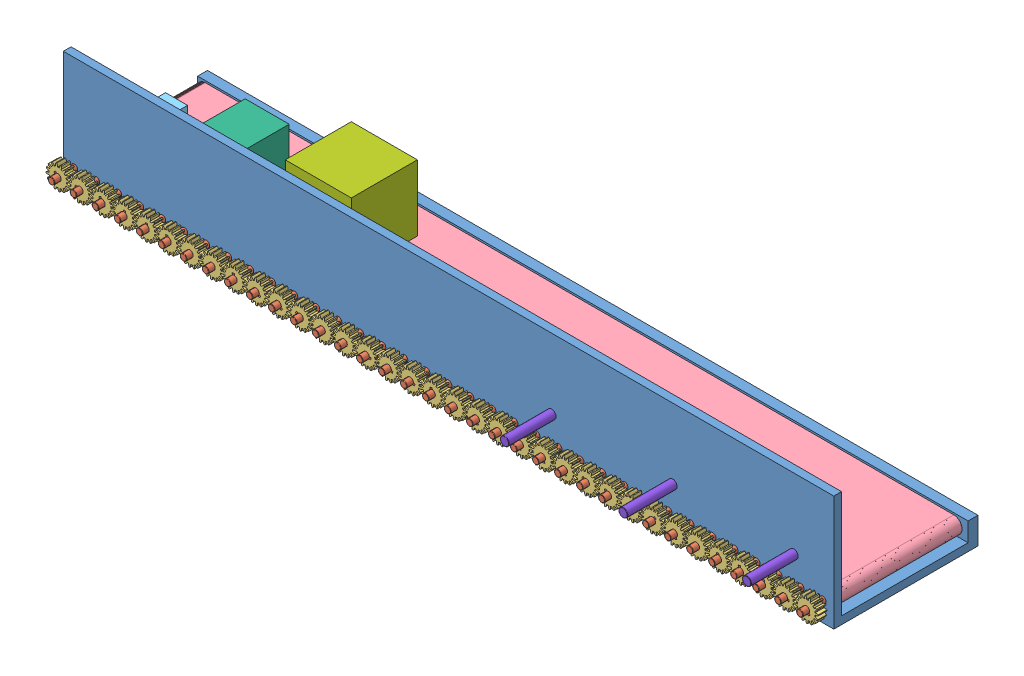
SolidWorks assembly Sorting Assembly, configuration Default. Lengths in mm.
Overall size (3549.93 523.7 880.63).
113 component instances, 8 part files, 186 mates.
Components (placement in the parent):
- part7-1: part7 [Default] at (1006.6553 1787.6179 2565.5497) size (3500 523.7 655)
- roller-37: roller [Default] at (-193.3447 1492.6179 3165.5497) x (-0.262739 0.964867 0) z (0 0 -1) size (75 75 750)
- roller-38: roller [Default] at (-593.3447 1492.6179 3165.5497) x (-0.948434 0.316975 0) z (0 0 -1) size (75 75 750)
- roller-39: roller [Default] at (-393.3447 1492.6179 3165.5497) x (0.151532 0.988452 0) z (0 0 -1) size (75 75 750)
- roller-40: roller [Default] at (-493.3447 1492.6179 3165.5497) x (-0.412809 0.910818 0) z (0 0 -1) size (75 75 750)
- roller-41: roller [Default] at (-293.3447 1492.6179 3165.5497) x (0.164944 0.986303 0) z (0 0 -1) size (75 75 750)
- roller-42: roller [Default] at (206.6553 1492.6179 3165.5497) x (0.853814 -0.520577 0) z (0 0 -1) size (75 75 750)
- roller-43: roller [Default] at (-93.3447 1492.6179 3165.5497) x (-0.222258 -0.974988 0) z (0 0 -1) size (75 75 750)
- roller-44: roller [Default] at (6.6553 1492.6179 3165.5497) x (-0.857308 -0.514803 0) z (0 0 -1) size (75 75 750)
- roller-45: roller [Default] at (106.6553 1492.6179 3165.5497) x (-0.150084 0.988673 0) z (0 0 -1) size (75 75 750)
- roller-46: roller [Default] at (406.6553 1492.6179 3165.5497) x (-0.853759 0.520669 0) z (0 0 -1) size (75 75 750)
- roller-47: roller [Default] at (306.6553 1492.6179 3165.5497) x (0.816925 -0.576744 0) z (0 0 -1) size (75 75 750)
- roller-48: roller [Default] at (706.6553 1492.6179 3165.5497) x (0.984729 -0.174094 0) z (0 0 -1) size (75 75 750)
- roller-49: roller [Default] at (806.6553 1492.6179 3165.5497) x (0.935909 -0.352242 0) z (0 0 -1) size (75 75 750)
- roller-50: roller [Default] at (506.6553 1492.6179 3165.5497) x (-0.352824 -0.93569 0) z (0 0 -1) size (75 75 750)
- roller-51: roller [Default] at (606.6553 1492.6179 3165.5497) x (-0.991808 -0.127741 0) z (0 0 -1) size (75 75 750)
- roller-52: roller [Default] at (1006.6553 1492.6179 3165.5497) x (-0.232726 0.972542 0) z (0 0 -1) size (75 75 750)
- roller-53: roller [Default] at (1106.6553 1492.6179 3165.5497) x (-0.541816 -0.840497 0) z (0 0 -1) size (75 75 750)
- roller-54: roller [Default] at (906.6553 1492.6179 3165.5497) x (0.950307 -0.311315 0) z (0 0 -1) size (75 75 750)
- roller-55: roller [Default] at (1406.6553 1492.6179 3165.5497) x (-0.071136 -0.997467 0) z (0 0 -1) size (75 75 750)
- roller-56: roller [Default] at (1506.6553 1492.6179 3165.5497) x (0.386535 -0.922275 0) z (0 0 -1) size (75 75 750)
- roller-57: roller [Default] at (1706.6553 1492.6179 3165.5497) x (-0.804149 0.594428 0) z (0 0 -1) size (75 75 750)
- roller-58: roller [Default] at (1606.6553 1492.6179 3165.5497) x (0.255994 -0.966678 0) z (0 0 -1) size (75 75 750)
- roller-59: roller [Default] at (1306.6553 1492.6179 3165.5497) x (-0.242252 -0.970213 0) z (0 0 -1) size (75 75 750)
- roller-60: roller [Default] at (1206.6553 1492.6179 3165.5497) x (0.281912 -0.95944 0) z (0 0 -1) size (75 75 750)
- roller-61: roller [Default] at (1906.6553 1492.6179 3165.5497) x (0.363631 0.931543 0) z (0 0 -1) size (75 75 750)
- roller-62: roller [Default] at (1806.6553 1492.6179 3165.5497) x (-0.647045 0.762452 0) z (0 0 -1) size (75 75 750)
- roller-63: roller [Default] at (2106.6553 1492.6179 3165.5497) x (0.357563 -0.933889 0) z (0 0 -1) size (75 75 750)
- roller-64: roller [Default] at (2306.6553 1492.6179 3165.5497) x (-0.138327 0.990387 0) z (0 0 -1) size (75 75 750)
- roller-65: roller [Default] at (2006.6553 1492.6179 3165.5497) x (0.609525 0.792767 0) z (0 0 -1) size (75 75 750)
- roller-66: roller [Default] at (2206.6553 1492.6179 3165.5497) x (-0.844121 -0.536153 0) z (0 0 -1) size (75 75 750)
- roller-67: roller [Default] at (2406.6553 1492.6179 3165.5497) x (-0.215061 0.976601 0) z (0 0 -1) size (75 75 750)
- roller-68: roller [Default] at (2606.6553 1492.6179 3165.5497) x (0.970522 -0.241014 0) z (0 0 -1) size (75 75 750)
- roller-69: roller [Default] at (2506.6553 1492.6179 3165.5497) x (0.299017 0.954248 0) z (0 0 -1) size (75 75 750)
- roller-70: roller [Default] at (-693.3447 1492.6179 3165.5497) x (-0.655751 0.754977 0) z (0 0 -1) size (75 75 750)
- roller-71: roller [Default] at (2706.6553 1492.6179 3165.5497) x (0.605336 -0.79597 0) z (0 0 -1) size (75 75 750)
- Gear-69: Gear [Default] at (2700.6849 1503.6627 3266.9494) x (0 0 -1) z (-0.79597 -0.605336 0) size (40 106.63 106.63)
  - spur gear_am-4: spur gear_am [Metric - Spur gear 6M 16T 14.5PA 40FW ---S16N75H50L30N] at (-18.6002 12.4054 1.9336) size (40 106.63 106.63)
- Gear-70: Gear [Default] at (2595.0816 1497.4844 3266.9494) x (0 0 -1) z (-0.241014 -0.970522 0) size (40 106.63 106.63)
  - spur gear_am-4: spur gear_am [Metric - Spur gear 6M 16T 14.5PA 40FW ---S16N75H50L30N] at (-18.6002 12.4054 1.9336) size (40 106.63 106.63)
- Gear-71: Gear [Default] at (2501.1007 1481.3582 3266.9494) x (0 0 -1) z (0.954248 -0.299017 0) size (40 106.63 106.63)
  - spur gear_am-4: spur gear_am [Metric - Spur gear 6M 16T 14.5PA 40FW ---S16N75H50L30N] at (-18.6002 12.4054 1.9336) size (40 106.63 106.63)
- Gear-72: Gear [Default] at (2407.4349 1480.0869 3266.9494) x (0 0 -1) z (0.976601 0.215061 0) size (40 106.63 106.63)
  - spur gear_am-4: spur gear_am [Metric - Spur gear 6M 16T 14.5PA 40FW ---S16N75H50L30N] at (-18.6002 12.4054 1.9336) size (40 106.63 106.63)
- Gear-73: Gear [Default] at (2306.4563 1480.0643 3266.9494) x (0 0 -1) z (0.990387 0.138327 0) size (40 106.63 106.63)
  - spur gear_am-4: spur gear_am [Metric - Spur gear 6M 16T 14.5PA 40FW ---S16N75H50L30N] at (-18.6002 12.4054 1.9336) size (40 106.63 106.63)
- Gear-74: Gear [Default] at (2218.1637 1497.637 3266.9494) x (0 0 -1) z (-0.536153 0.844121 0) size (40 106.63 106.63)
  - spur gear_am-4: spur gear_am [Metric - Spur gear 6M 16T 14.5PA 40FW ---S16N75H50L30N] at (-18.6002 12.4054 1.9336) size (40 106.63 106.63)
- Gear-75: Gear [Default] at (1997.561 1483.9619 3266.9494) x (0 0 -1) z (0.792767 -0.609525 0) size (40 106.63 106.63)
  - spur gear_am-4: spur gear_am [Metric - Spur gear 6M 16T 14.5PA 40FW ---S16N75H50L30N] at (-18.6002 12.4054 1.9336) size (40 106.63 106.63)
- Gear-76: Gear [Default] at (1900.3431 1481.7648 3266.9494) x (0 0 -1) z (0.931543 -0.363631 0) size (40 106.63 106.63)
  - spur gear_am-4: spur gear_am [Metric - Spur gear 6M 16T 14.5PA 40FW ---S16N75H50L30N] at (-18.6002 12.4054 1.9336) size (40 106.63 106.63)
- Gear-77: Gear [Default] at (2104.0253 1504.8946 3266.9494) x (0 0 -1) z (-0.933889 -0.357563 0) size (40 106.63 106.63)
  - spur gear_am-4: spur gear_am [Metric - Spur gear 6M 16T 14.5PA 40FW ---S16N75H50L30N] at (-18.6002 12.4054 1.9336) size (40 106.63 106.63)
- Gear-78: Gear [Default] at (1813.2079 1481.9083 3266.9494) x (0 0 -1) z (0.762452 0.647045 0) size (40 106.63 106.63)
  - spur gear_am-4: spur gear_am [Metric - Spur gear 6M 16T 14.5PA 40FW ---S16N75H50L30N] at (-18.6002 12.4054 1.9336) size (40 106.63 106.63)
- Gear-79: Gear [Default] at (1715.4817 1483.6889 3266.9494) x (0 0 -1) z (0.594428 0.804149 0) size (40 106.63 106.63)
  - spur gear_am-4: spur gear_am [Metric - Spur gear 6M 16T 14.5PA 40FW ---S16N75H50L30N] at (-18.6002 12.4054 1.9336) size (40 106.63 106.63)
- Gear-80: Gear [Default] at (1605.3487 1505.105 3266.9494) x (0 0 -1) z (-0.966678 -0.255994 0) size (40 106.63 106.63)
  - spur gear_am-4: spur gear_am [Metric - Spur gear 6M 16T 14.5PA 40FW ---S16N75H50L30N] at (-18.6002 12.4054 1.9336) size (40 106.63 106.63)
- Gear-81: Gear [Default] at (1503.6434 1504.8065 3266.9494) x (0 0 -1) z (-0.922275 -0.386535 0) size (40 106.63 106.63)
  - spur gear_am-4: spur gear_am [Metric - Spur gear 6M 16T 14.5PA 40FW ---S16N75H50L30N] at (-18.6002 12.4054 1.9336) size (40 106.63 106.63)
- Gear-82: Gear [Default] at (1409.4664 1504.8544 3266.9494) x (0 0 -1) z (-0.997467 0.071136 0) size (40 106.63 106.63)
  - spur gear_am-4: spur gear_am [Metric - Spur gear 6M 16T 14.5PA 40FW ---S16N75H50L30N] at (-18.6002 12.4054 1.9336) size (40 106.63 106.63)
- Gear-83: Gear [Default] at (1205.0132 1505.0653 3266.9494) x (0 0 -1) z (-0.95944 -0.281912 0) size (40 106.63 106.63)
  - spur gear_am-4: spur gear_am [Metric - Spur gear 6M 16T 14.5PA 40FW ---S16N75H50L30N] at (-18.6002 12.4054 1.9336) size (40 106.63 106.63)
- Gear-84: Gear [Default] at (1311.5365 1504.1854 3266.9494) x (0 0 -1) z (-0.970213 0.242252 0) size (40 106.63 106.63)
  - spur gear_am-4: spur gear_am [Metric - Spur gear 6M 16T 14.5PA 40FW ---S16N75H50L30N] at (-18.6002 12.4054 1.9336) size (40 106.63 106.63)
- Gear-85: Gear [Default] at (1007.6619 1480.1031 3266.9494) x (0 0 -1) z (0.972542 0.232726 0) size (40 106.63 106.63)
  - spur gear_am-4: spur gear_am [Metric - Spur gear 6M 16T 14.5PA 40FW ---S16N75H50L30N] at (-18.6002 12.4054 1.9336) size (40 106.63 106.63)
- Gear-86: Gear [Default] at (895.4683 1498.3174 3266.9494) x (0 0 -1) z (-0.311315 -0.950307 0) size (40 106.63 106.63)
  - spur gear_am-4: spur gear_am [Metric - Spur gear 6M 16T 14.5PA 40FW ---S16N75H50L30N] at (-18.6002 12.4054 1.9336) size (40 106.63 106.63)
- Gear-87: Gear [Default] at (795.726 1498.7973 3266.9494) x (0 0 -1) z (-0.352242 -0.935909 0) size (40 106.63 106.63)
  - spur gear_am-4: spur gear_am [Metric - Spur gear 6M 16T 14.5PA 40FW ---S16N75H50L30N] at (-18.6002 12.4054 1.9336) size (40 106.63 106.63)
- Gear-88: Gear [Default] at (1115.0019 1501.997 3266.9494) x (0 0 -1) z (-0.840497 0.541816 0) size (40 106.63 106.63)
  - spur gear_am-4: spur gear_am [Metric - Spur gear 6M 16T 14.5PA 40FW ---S16N75H50L30N] at (-18.6002 12.4054 1.9336) size (40 106.63 106.63)
- Gear-89: Gear [Default] at (694.7759 1496.6817 3266.9494) x (0 0 -1) z (-0.174094 -0.984729 0) size (40 106.63 106.63)
  - spur gear_am-4: spur gear_am [Metric - Spur gear 6M 16T 14.5PA 40FW ---S16N75H50L30N] at (-18.6002 12.4054 1.9336) size (40 106.63 106.63)
- Gear-90: Gear [Default] at (106.6055 1480.0628 3266.9494) x (0 0 -1) z (0.988673 0.150084 0) size (40 106.63 106.63)
  - spur gear_am-4: spur gear_am [Metric - Spur gear 6M 16T 14.5PA 40FW ---S16N75H50L30N] at (-18.6002 12.4054 1.9336) size (40 106.63 106.63)
- Gear-91: Gear [Default] at (297.6362 1501.3523 3266.9494) x (0 0 -1) z (-0.576744 -0.816925 0) size (40 106.63 106.63)
  - spur gear_am-4: spur gear_am [Metric - Spur gear 6M 16T 14.5PA 40FW ---S16N75H50L30N] at (-18.6002 12.4054 1.9336) size (40 106.63 106.63)
- Gear-92: Gear [Default] at (416.2398 1484.508 3266.9494) x (0 0 -1) z (0.520669 0.853759 0) size (40 106.63 106.63)
  - spur gear_am-4: spur gear_am [Metric - Spur gear 6M 16T 14.5PA 40FW ---S16N75H50L30N] at (-18.6002 12.4054 1.9336) size (40 106.63 106.63)
- Gear-93: Gear [Default] at (512.8415 1503.5434 3266.9494) x (0 0 -1) z (-0.93569 0.352824 0) size (40 106.63 106.63)
  - spur gear_am-4: spur gear_am [Metric - Spur gear 6M 16T 14.5PA 40FW ---S16N75H50L30N] at (-18.6002 12.4054 1.9336) size (40 106.63 106.63)
- Gear-94: Gear [Default] at (619.2061 1492.2849 3266.9494) x (0 0 -1) z (-0.127741 0.991808 0) size (40 106.63 106.63)
  - spur gear_am-4: spur gear_am [Metric - Spur gear 6M 16T 14.5PA 40FW ---S16N75H50L30N] at (-18.6002 12.4054 1.9336) size (40 106.63 106.63)
- Gear-95: Gear [Default] at (-191.951 1480.1403 3266.9494) x (0 0 -1) z (0.964867 0.262739 0) size (40 106.63 106.63)
  - spur gear_am-4: spur gear_am [Metric - Spur gear 6M 16T 14.5PA 40FW ---S16N75H50L30N] at (-18.6002 12.4054 1.9336) size (40 106.63 106.63)
- Gear-96: Gear [Default] at (-88.7023 1504.2833 3266.9494) x (0 0 -1) z (-0.974988 0.222258 0) size (40 106.63 106.63)
  - spur gear_am-4: spur gear_am [Metric - Spur gear 6M 16T 14.5PA 40FW ---S16N75H50L30N] at (-18.6002 12.4054 1.9336) size (40 106.63 106.63)
- Gear-97: Gear [Default] at (18.286 1497.3466 3266.9494) x (0 0 -1) z (-0.514803 0.857308 0) size (40 106.63 106.63)
  - spur gear_am-4: spur gear_am [Metric - Spur gear 6M 16T 14.5PA 40FW ---S16N75H50L30N] at (-18.6002 12.4054 1.9336) size (40 106.63 106.63)
- Gear-98: Gear [Default] at (197.0699 1500.7268 3266.9494) x (0 0 -1) z (-0.520577 -0.853814 0) size (40 106.63 106.63)
  - spur gear_am-4: spur gear_am [Metric - Spur gear 6M 16T 14.5PA 40FW ---S16N75H50L30N] at (-18.6002 12.4054 1.9336) size (40 106.63 106.63)
- Gear-99: Gear [Default] at (-297.298 1480.7013 3266.9494) x (0 0 -1) z (0.986303 -0.164944 0) size (40 106.63 106.63)
  - spur gear_am-4: spur gear_am [Metric - Spur gear 6M 16T 14.5PA 40FW ---S16N75H50L30N] at (-18.6002 12.4054 1.9336) size (40 106.63 106.63)
- Gear-100: Gear [Default] at (-397.1358 1480.6487 3266.9494) x (0 0 -1) z (0.988452 -0.151532 0) size (40 106.63 106.63)
  - spur gear_am-4: spur gear_am [Metric - Spur gear 6M 16T 14.5PA 40FW ---S16N75H50L30N] at (-18.6002 12.4054 1.9336) size (40 106.63 106.63)
- Gear-101: Gear [Default] at (-582.1919 1486.8518 3266.9494) x (0 0 -1) z (0.316975 0.948434 0) size (40 106.63 106.63)
  - spur gear_am-4: spur gear_am [Metric - Spur gear 6M 16T 14.5PA 40FW ---S16N75H50L30N] at (-18.6002 12.4054 1.9336) size (40 106.63 106.63)
- Gear-102: Gear [Default] at (-489.9848 1480.5206 3266.9494) x (0 0 -1) z (0.910818 0.412809 0) size (40 106.63 106.63)
  - spur gear_am-4: spur gear_am [Metric - Spur gear 6M 16T 14.5PA 40FW ---S16N75H50L30N] at (-18.6002 12.4054 1.9336) size (40 106.63 106.63)
- Gear-103: Gear [Default] at (-686.6696 1481.9841 3266.9494) x (0 0 -1) z (0.754977 0.655751 0) size (40 106.63 106.63)
  - spur gear_am-4: spur gear_am [Metric - Spur gear 6M 16T 14.5PA 40FW ---S16N75H50L30N] at (-18.6002 12.4054 1.9336) size (40 106.63 106.63)
- Conveyor belt-2: Conveyor belt [Default] at (2431.395 1480.1179 2615.5497) size (3475 75 550)
- box 10-1: box 10 [Default] at (-593.8508 1580.7982 2845.6293) size (100 100 100)
- box 20-1: box 20 [Default] at (-238.4985 1631.1131 2789.3903) size (200 200 200)
- box 30-1: box 30 [Default] at (242.1467 1680.6163 2737.9079) size (300 300 300)
- arm-4: arm [Default] at (2024.9414 1607.6179 3436.1766) x (0 -1 0) z (0 0 -1) size (99.61 80 294)
- arm-5: arm [Default] at (2574.8267 1607.6179 3424.7444) x (0 -1 0) z (0 0 -1) size (99.61 80 294)
- arm-6: arm [Default] at (1474.9414 1607.6179 3424.6173) x (0 -1 0) z (0 0 -1) size (99.61 80 294)
Mates (geometry in assembly coordinates):
- Concentric37: concentric: cylinder of part7-1 through (-593.3447 1492.6179 2565.5497) axis (0 0 1) radius 15; cylinder of roller-38 through (-593.3447 1492.6179 2565.5497) axis (0 0 1) radius 15
- Coincident40: coincident: circle of part7-1; circle of roller-38
- Concentric38: concentric: cylinder of part7-1 through (-493.3447 1492.6179 2565.5497) axis (0 0 1) radius 15; cylinder of roller-40 through (-493.3447 1492.6179 2565.5497) axis (0 0 1) radius 15
- Coincident41: coincident: circle of part7-1; circle of roller-40
- Concentric39: concentric: cylinder of part7-1 through (-393.3447 1492.6179 2565.5497) axis (0 0 1) radius 15; cylinder of roller-39 through (-393.3447 1492.6179 2565.5497) axis (0 0 1) radius 15
- Coincident42: coincident: circle of part7-1; circle of roller-39
- Concentric40: concentric: cylinder of part7-1 through (-293.3447 1492.6179 2565.5497) axis (0 0 1) radius 15; cylinder of roller-41 through (-293.3447 1492.6179 2565.5497) axis (0 0 1) radius 15
- Coincident43: coincident: circle of part7-1; circle of roller-41
- Concentric41: concentric: cylinder of part7-1 through (-193.3447 1492.6179 2565.5497) axis (0 0 1) radius 15; cylinder of roller-37 through (-193.3447 1492.6179 2565.5497) axis (0 0 1) radius 15
- Coincident44: coincident: circle of part7-1; circle of roller-37
- Concentric42: concentric: cylinder of part7-1 through (-93.3447 1492.6179 2565.5497) axis (0 0 1) radius 15; cylinder of roller-43 through (-93.3447 1492.6179 2565.5497) axis (0 0 1) radius 15
- Coincident45: coincident: circle of part7-1; circle of roller-43
- Concentric43: concentric: cylinder of part7-1 through (6.6553 1492.6179 2565.5497) axis (0 0 1) radius 15; cylinder of roller-44 through (6.6553 1492.6179 2565.5497) axis (0 0 1) radius 15
- Coincident46: coincident: circle of part7-1; circle of roller-44
- Concentric44: concentric: cylinder of part7-1 through (106.6553 1492.6179 2565.5497) axis (0 0 1) radius 15; cylinder of roller-45 through (106.6553 1492.6179 2565.5497) axis (0 0 1) radius 15
- Coincident47: coincident: circle of part7-1; circle of roller-45
- Concentric45: concentric: cylinder of part7-1 through (206.6553 1492.6179 2565.5497) axis (0 0 1) radius 15; cylinder of roller-42 through (206.6553 1492.6179 2565.5497) axis (0 0 1) radius 15
- Coincident49: coincident: circle of part7-1; circle of roller-42
- Concentric46: concentric: cylinder of part7-1 through (306.6553 1492.6179 2565.5497) axis (0 0 1) radius 15; cylinder of roller-47 through (306.6553 1492.6179 2565.5497) axis (0 0 1) radius 15
- Coincident50: coincident: circle of part7-1; circle of roller-47
- Concentric47: concentric: cylinder of part7-1 through (406.6553 1492.6179 2565.5497) axis (0 0 1) radius 15; cylinder of roller-46 through (406.6553 1492.6179 2565.5497) axis (0 0 1) radius 15
- Coincident51: coincident: circle of part7-1; circle of roller-46
- Concentric48: concentric: cylinder of part7-1 through (506.6553 1492.6179 2565.5497) axis (0 0 1) radius 15; cylinder of roller-50 through (506.6553 1492.6179 2565.5497) axis (0 0 1) radius 15
- Coincident52: coincident: circle of part7-1; circle of roller-50
- Concentric49: concentric: cylinder of part7-1 through (606.6553 1492.6179 2565.5497) axis (0 0 1) radius 15; cylinder of roller-51 through (606.6553 1492.6179 2565.5497) axis (0 0 1) radius 15
- Coincident53: coincident: circle of part7-1; circle of roller-51
- Concentric50: concentric: cylinder of part7-1 through (706.6553 1492.6179 2565.5497) axis (0 0 1) radius 15; cylinder of roller-48 through (706.6553 1492.6179 2565.5497) axis (0 0 1) radius 15
- Coincident54: coincident: circle of part7-1; circle of roller-48
- Concentric51: concentric: cylinder of part7-1 through (806.6553 1492.6179 2565.5497) axis (0 0 1) radius 15; cylinder of roller-49 through (806.6553 1492.6179 2565.5497) axis (0 0 1) radius 15
- Coincident55: coincident: circle of part7-1; circle of roller-49
- Concentric52: concentric: cylinder of part7-1 through (906.6553 1492.6179 2565.5497) axis (0 0 1) radius 15; cylinder of roller-54 through (906.6553 1492.6179 2565.5497) axis (0 0 1) radius 15
- Coincident56: coincident: circle of part7-1; circle of roller-54
- Concentric53: concentric: cylinder of part7-1 through (1006.6553 1492.6179 2565.5497) axis (0 0 1) radius 15; cylinder of roller-52 through (1006.6553 1492.6179 2565.5497) axis (0 0 1) radius 15
- Coincident57: coincident: circle of part7-1; circle of roller-52
- Concentric54: concentric: cylinder of part7-1 through (1106.6553 1492.6179 2565.5497) axis (0 0 1) radius 15; cylinder of roller-53 through (1106.6553 1492.6179 2565.5497) axis (0 0 1) radius 15
- Coincident58: coincident: circle of part7-1; circle of roller-53
- Concentric55: concentric: cylinder of part7-1 through (1206.6553 1492.6179 2565.5497) axis (0 0 1) radius 15; cylinder of roller-60 through (1206.6553 1492.6179 2565.5497) axis (0 0 1) radius 15
- Coincident59: coincident: circle of part7-1; circle of roller-60
- Concentric56: concentric: cylinder of part7-1 through (1306.6553 1492.6179 2565.5497) axis (0 0 1) radius 15; cylinder of roller-59 through (1306.6553 1492.6179 2565.5497) axis (0 0 1) radius 15
- Coincident60: coincident: circle of part7-1; circle of roller-59
- Concentric57: concentric: cylinder of part7-1 through (1406.6553 1492.6179 2565.5497) axis (0 0 1) radius 15; cylinder of roller-55 through (1406.6553 1492.6179 2565.5497) axis (0 0 1) radius 15
- Coincident61: coincident: circle of part7-1; circle of roller-55
- Concentric58: concentric: cylinder of part7-1 through (1506.6553 1492.6179 2565.5497) axis (0 0 1) radius 15; cylinder of roller-56 through (1506.6553 1492.6179 2565.5497) axis (0 0 1) radius 15
- Coincident62: coincident: circle of part7-1; circle of roller-56
- Concentric59: concentric: cylinder of part7-1 through (1606.6553 1492.6179 2565.5497) axis (0 0 1) radius 15; cylinder of roller-58 through (1606.6553 1492.6179 2565.5497) axis (0 0 1) radius 15
- Coincident63: coincident: circle of part7-1; circle of roller-58
- Concentric60: concentric: cylinder of part7-1 through (1706.6553 1492.6179 2565.5497) axis (0 0 1) radius 15; cylinder of roller-57 through (1706.6553 1492.6179 2565.5497) axis (0 0 1) radius 15
- Coincident64: coincident: circle of part7-1; circle of roller-57
- Concentric61: concentric: cylinder of part7-1 through (1806.6553 1492.6179 2565.5497) axis (0 0 1) radius 15; cylinder of roller-62 through (1806.6553 1492.6179 2565.5497) axis (0 0 1) radius 15
- Coincident65: coincident: circle of part7-1; circle of roller-62
- Concentric62: concentric: cylinder of part7-1 through (1906.6553 1492.6179 2565.5497) axis (0 0 1) radius 15; cylinder of roller-61 through (1906.6553 1492.6179 2565.5497) axis (0 0 1) radius 15
- Coincident66: coincident: circle of part7-1; circle of roller-61
- Concentric63: concentric: cylinder of part7-1 through (2006.6553 1492.6179 2565.5497) axis (0 0 1) radius 15; cylinder of roller-65 through (2006.6553 1492.6179 2565.5497) axis (0 0 1) radius 15
- Coincident67: coincident: circle of part7-1; circle of roller-65
- Concentric64: concentric: cylinder of part7-1 through (2106.6553 1492.6179 2565.5497) axis (0 0 1) radius 15; cylinder of roller-63 through (2106.6553 1492.6179 2565.5497) axis (0 0 1) radius 15
- Coincident68: coincident: circle of part7-1; circle of roller-63
- Concentric65: concentric: cylinder of part7-1 through (2206.6553 1492.6179 2565.5497) axis (0 0 1) radius 15; cylinder of roller-66 through (2206.6553 1492.6179 2565.5497) axis (0 0 1) radius 15
- Coincident69: coincident: circle of part7-1; circle of roller-66
- Concentric66: concentric: cylinder of part7-1 through (2306.6553 1492.6179 2565.5497) axis (0 0 1) radius 15; cylinder of roller-64 through (2306.6553 1492.6179 2565.5497) axis (0 0 1) radius 15
- Coincident70: coincident: circle of part7-1; circle of roller-64
- Concentric67: concentric: cylinder of part7-1 through (2406.6553 1492.6179 2565.5497) axis (0 0 1) radius 15; cylinder of roller-67 through (2406.6553 1492.6179 2565.5497) axis (0 0 1) radius 15
- Coincident71: coincident: circle of part7-1; circle of roller-67
- Concentric68: concentric: cylinder of part7-1 through (2506.6553 1492.6179 2565.5497) axis (0 0 1) radius 15; cylinder of roller-69 through (2506.6553 1492.6179 2565.5497) axis (0 0 1) radius 15
- Coincident72: coincident: circle of part7-1; circle of roller-69
- Concentric69: concentric: cylinder of part7-1 through (2606.6553 1492.6179 2565.5497) axis (0 0 1) radius 15; cylinder of roller-68 through (2606.6553 1492.6179 2565.5497) axis (0 0 1) radius 15
- Coincident73: coincident: circle of part7-1; circle of roller-68
- Concentric70: concentric: cylinder of part7-1 through (-693.3447 1492.6179 2565.5497) axis (0 0 1) radius 15; cylinder of roller-70 through (-693.3447 1492.6179 2565.5497) axis (0 0 1) radius 15
- Coincident74: coincident: circle of part7-1; circle of roller-70
- Concentric71: concentric: cylinder of part7-1 through (2706.6553 1492.6179 2565.5497) axis (0 0 1) radius 15; cylinder of roller-71 through (2706.6553 1492.6179 2565.5497) axis (0 0 1) radius 15
- Coincident76: coincident: circle of part7-1; circle of roller-71
- Concentric72: concentric: cylinder of roller-71 through (2706.6553 1492.6179 3315.5497) axis (0 0 -1) radius 15; cylinder of Gear-69/spur gear_am-4 through (2706.6553 1492.6179 3235.5496) axis (0 0 1) radius 15
- Coincident77: coincident: line of roller-71 through (2723.9525 1478.1333 3285.5497) axis (-0.79597 -0.605336 0); line of Gear-69/spur gear_am-4 through (2723.9525 1478.1333 3285.5497) axis (-0.79597 -0.605336 0)
- Concentric75: concentric: cylinder of roller-68 through (2606.6553 1492.6179 3315.5497) axis (0 0 -1) radius 15; cylinder of Gear-70/spur gear_am-4 through (2606.6553 1492.6179 3235.5496) axis (0 0 1) radius 15
- Coincident80: coincident: line of roller-68 through (2629.2118 1492.1682 3285.5497) axis (-0.241014 -0.970522 0); line of Gear-70/spur gear_am-4 through (2629.2118 1492.1682 3285.5497) axis (-0.241014 -0.970522 0)
- GearMate3: gear = 30 : 30 mm: circle of Gear-69/spur gear_am-4; cylinder of Gear-70/spur gear_am-4 through (2606.6553 1492.6179 3245.5497) axis (0 0 1) radius 40.499
- Concentric76: concentric: cylinder of roller-69 through (2506.6553 1492.6179 3315.5497) axis (0 0 -1) radius 15; cylinder of Gear-71/spur gear_am-4 through (2506.6553 1492.6179 3235.5496) axis (0 0 1) radius 15
- Coincident81: coincident: line of roller-69 through (2508.4624 1515.1065 3285.5497) axis (0.954248 -0.299017 0); line of Gear-71/spur gear_am-4 through (2508.4624 1515.1065 3285.5497) axis (0.954248 -0.299017 0)
- Concentric77: concentric: cylinder of roller-67 through (2406.6553 1492.6179 3315.5497) axis (0 0 -1) radius 15; cylinder of Gear-72/spur gear_am-4 through (2406.6553 1492.6179 3235.5496) axis (0 0 1) radius 15
- Coincident82: coincident: line of roller-67 through (2397.0409 1513.0278 3285.5497) axis (0.976601 0.215061 0); line of Gear-72/spur gear_am-4 through (2397.0409 1513.0278 3285.5497) axis (0.976601 0.215061 0)
- GearMate4: gear = 30 : 30 mm: circle of Gear-70/spur gear_am-4; circle of Gear-71/spur gear_am-4
- Concentric78: concentric: cylinder of roller-64 through (2306.6553 1492.6179 3315.5497) axis (0 0 -1) radius 15; cylinder of Gear-73/spur gear_am-4 through (2306.6553 1492.6179 3235.5496) axis (0 0 1) radius 15
- Coincident83: coincident: line of roller-64 through (2298.6602 1513.7148 3285.5497) axis (0.990387 0.138327 0); line of Gear-73/spur gear_am-4 through (2298.6602 1513.7148 3285.5497) axis (0.990387 0.138327 0)
- GearMate5: gear = 30 : 30 mm: circle of Gear-71/spur gear_am-4; circle of Gear-72/spur gear_am-4
- GearMate6: gear = 30 : 30 mm: circle of Gear-72/spur gear_am-4; circle of Gear-73/spur gear_am-4
- Concentric79: concentric: cylinder of roller-66 through (2206.6553 1492.6179 3315.5497) axis (0 0 -1) radius 15; cylinder of Gear-74/spur gear_am-4 through (2206.6553 1492.6179 3235.5496) axis (0 0 1) radius 15
- Coincident84: coincident: line of roller-66 through (2190.7654 1476.602 3285.5497) axis (-0.536153 0.844121 0); line of Gear-74/spur gear_am-4 through (2190.7654 1476.602 3285.5497) axis (-0.536153 0.844121 0)
- Concentric80: concentric: cylinder of roller-63 through (2106.6553 1492.6179 3315.5497) axis (0 0 -1) radius 15; cylinder of Gear-77/spur gear_am-4 through (2106.6553 1492.6179 3235.5496) axis (0 0 1) radius 15
- Coincident85: coincident: line of roller-63 through (2119.1911 1473.8602 3285.5497) axis (-0.933889 -0.357563 0); line of Gear-77/spur gear_am-4 through (2119.1911 1473.8602 3285.5497) axis (-0.933889 -0.357563 0)
- Concentric81: concentric: cylinder of roller-65 through (2006.6553 1492.6179 3315.5497) axis (0 0 -1) radius 15; cylinder of Gear-75/spur gear_am-4 through (2006.6553 1492.6179 3235.5496) axis (0 0 1) radius 15
- Coincident86: coincident: line of roller-65 through (2016.101 1513.1064 3285.5497) axis (0.792767 -0.609525 0); line of Gear-75/spur gear_am-4 through (2016.101 1513.1064 3285.5497) axis (0.792767 -0.609525 0)
- Concentric82: concentric: cylinder of roller-61 through (1906.6553 1492.6179 3315.5497) axis (0 0 -1) radius 15; cylinder of Gear-76/spur gear_am-4 through (1906.6553 1492.6179 3235.5496) axis (0 0 1) radius 15
- Coincident87: coincident: line of roller-61 through (1909.9975 1514.93 3285.5497) axis (0.931543 -0.363631 0); line of Gear-76/spur gear_am-4 through (1909.9975 1514.93 3285.5497) axis (0.931543 -0.363631 0)
- GearMate7: gear = 30 : 30 mm: circle of Gear-73/spur gear_am-4; circle of Gear-74/spur gear_am-4
- GearMate8: gear = 30 : 30 mm: circle of Gear-74/spur gear_am-4; circle of Gear-77/spur gear_am-4
- GearMate9: gear = 30 : 30 mm: circle of Gear-75/spur gear_am-4; circle of Gear-77/spur gear_am-4
- GearMate10: gear = 30 : 30 mm: circle of Gear-75/spur gear_am-4; circle of Gear-76/spur gear_am-4
- Concentric83: concentric: cylinder of roller-62 through (1806.6553 1492.6179 3315.5497) axis (0 0 -1) radius 15; cylinder of Gear-78/spur gear_am-4 through (1806.6553 1492.6179 3235.5496) axis (0 0 1) radius 15
- Coincident88: coincident: line of roller-62 through (1788.608 1506.1566 3285.5497) axis (0.762452 0.647045 0); line of Gear-78/spur gear_am-4 through (1788.608 1506.1566 3285.5497) axis (0.762452 0.647045 0)
- GearMate11: gear = 30 : 30 mm: circle of Gear-76/spur gear_am-4; circle of Gear-78/spur gear_am-4
- Concentric84: concentric: cylinder of roller-57 through (1706.6553 1492.6179 3315.5497) axis (0 0 -1) radius 15; cylinder of Gear-79/spur gear_am-4 through (1706.6553 1492.6179 3235.5496) axis (0 0 1) radius 15
- Coincident89: coincident: line of roller-57 through (1685.9919 1501.6746 3285.5497) axis (0.594428 0.804149 0); line of Gear-79/spur gear_am-4 through (1685.9919 1501.6746 3285.5497) axis (0.594428 0.804149 0)
- GearMate12: gear = 30 : 30 mm: circle of Gear-78/spur gear_am-4; circle of Gear-79/spur gear_am-4
- Concentric85: concentric: cylinder of roller-58 through (1606.6553 1492.6179 3315.5497) axis (0 0 -1) radius 15; cylinder of Gear-80/spur gear_am-4 through (1606.6553 1492.6179 3235.5496) axis (0 0 1) radius 15
- Coincident90: coincident: line of roller-58 through (1617.1206 1472.631 3285.5497) axis (-0.966678 -0.255994 0); line of Gear-80/spur gear_am-4 through (1617.1206 1472.631 3285.5497) axis (-0.966678 -0.255994 0)
- GearMate13: gear = 30 : 30 mm: circle of Gear-80/spur gear_am-4; circle of Gear-79/spur gear_am-4
- Concentric86: concentric: cylinder of roller-56 through (1506.6553 1492.6179 3315.5497) axis (0 0 -1) radius 15; cylinder of Gear-81/spur gear_am-4 through (1506.6553 1492.6179 3235.5496) axis (0 0 1) radius 15
- Coincident91: coincident: line of roller-56 through (1519.7704 1474.2606 3285.5497) axis (-0.922275 -0.386535 0); line of Gear-81/spur gear_am-4 through (1519.7704 1474.2606 3285.5497) axis (-0.922275 -0.386535 0)
- GearMate14: gear = 30 : 30 mm: circle of Gear-81/spur gear_am-4; circle of Gear-80/spur gear_am-4
- Concentric87: concentric: cylinder of roller-55 through (1406.6553 1492.6179 3315.5497) axis (0 0 -1) radius 15; cylinder of Gear-82/spur gear_am-4 through (1406.6553 1492.6179 3235.5496) axis (0 0 1) radius 15
- Coincident94: coincident: line of roller-55 through (1410.0776 1470.318 3285.5497) axis (-0.997467 0.071136 0); line of Gear-82/spur gear_am-4 through (1410.0776 1470.318 3285.5497) axis (-0.997467 0.071136 0)
- GearMate15: gear = 30 : 30 mm: circle of Gear-82/spur gear_am-4; circle of Gear-81/spur gear_am-4
- Concentric88: concentric: cylinder of roller-59 through (1306.6553 1492.6179 3315.5497) axis (0 0 -1) radius 15; cylinder of Gear-84/spur gear_am-4 through (1306.6553 1492.6179 3235.5496) axis (0 0 1) radius 15
- Coincident95: coincident: line of roller-59 through (1306.1768 1470.062 3285.5497) axis (-0.970213 0.242252 0); line of Gear-84/spur gear_am-4 through (1306.1768 1470.062 3285.5497) axis (-0.970213 0.242252 0)
- GearMate16: gear = 30 : 30 mm: circle of Gear-84/spur gear_am-4; circle of Gear-82/spur gear_am-4
- Concentric89: concentric: cylinder of roller-60 through (1206.6553 1492.6179 3315.5497) axis (0 0 -1) radius 15; cylinder of Gear-83/spur gear_am-4 through (1206.6553 1492.6179 3235.5496) axis (0 0 1) radius 15
- Coincident96: coincident: line of roller-60 through (1217.6546 1472.9198 3285.5497) axis (-0.95944 -0.281912 0); line of Gear-83/spur gear_am-4 through (1217.6546 1472.9198 3285.5497) axis (-0.95944 -0.281912 0)
- GearMate17: gear = 30 : 30 mm: circle of Gear-83/spur gear_am-4; circle of Gear-84/spur gear_am-4
- Concentric90: concentric: cylinder of roller-53 through (1106.6553 1492.6179 3315.5497) axis (0 0 -1) radius 15; cylinder of Gear-88/spur gear_am-4 through (1106.6553 1492.6179 3235.5496) axis (0 0 1) radius 15
- Coincident98: coincident: line of roller-53 through (1098.9378 1471.4179 3285.5497) axis (-0.840497 0.541816 0); line of Gear-88/spur gear_am-4 through (1098.9378 1471.4179 3285.5497) axis (-0.840497 0.541816 0)
- GearMate18: gear = 30 : 30 mm: circle of Gear-88/spur gear_am-4; circle of Gear-83/spur gear_am-4
- Concentric91: concentric: cylinder of roller-52 through (1006.6553 1492.6179 3315.5497) axis (0 0 -1) radius 15; cylinder of Gear-85/spur gear_am-4 through (1006.6553 1492.6179 3235.5496) axis (0 0 1) radius 15
- Coincident99: coincident: line of roller-52 through (996.6726 1512.8502 3285.5497) axis (0.972542 0.232726 0); line of Gear-85/spur gear_am-4 through (996.6726 1512.8502 3285.5497) axis (0.972542 0.232726 0)
- GearMate19: gear = 30 : 30 mm: circle of Gear-85/spur gear_am-4; circle of Gear-88/spur gear_am-4
- Concentric92: concentric: cylinder of roller-54 through (906.6553 1492.6179 3315.5497) axis (0 0 -1) radius 15; cylinder of Gear-86/spur gear_am-4 through (906.6553 1492.6179 3235.5496) axis (0 0 1) radius 15
- Coincident100: coincident: line of roller-54 through (929.1186 1490.5205 3285.5497) axis (-0.311315 -0.950307 0); line of Gear-86/spur gear_am-4 through (929.1186 1490.5205 3285.5497) axis (-0.311315 -0.950307 0)
- GearMate20: gear = 30 : 30 mm: circle of Gear-86/spur gear_am-4; circle of Gear-85/spur gear_am-4
- Concentric93: concentric: cylinder of roller-49 through (806.6553 1492.6179 3315.5497) axis (0 0 -1) radius 15; cylinder of Gear-87/spur gear_am-4 through (806.6553 1492.6179 3235.5496) axis (0 0 1) radius 15
- Coincident101: coincident: line of roller-49 through (829.0065 1489.5481 3285.5497) axis (-0.352242 -0.935909 0); line of Gear-87/spur gear_am-4 through (829.0065 1489.5481 3285.5497) axis (-0.352242 -0.935909 0)
- GearMate21: gear = 30 : 30 mm: circle of Gear-86/spur gear_am-4; circle of Gear-87/spur gear_am-4
- Concentric94: concentric: cylinder of roller-48 through (706.6553 1492.6179 3315.5497) axis (0 0 -1) radius 15; cylinder of Gear-89/spur gear_am-4 through (706.6553 1492.6179 3235.5496) axis (0 0 1) radius 15
- Coincident102: coincident: line of roller-48 through (729.1898 1493.7115 3285.5497) axis (-0.174094 -0.984729 0); line of Gear-89/spur gear_am-4 through (729.1898 1493.7115 3285.5497) axis (-0.174094 -0.984729 0)
- GearMate22: gear = 30 : 30 mm: circle of Gear-89/spur gear_am-4; circle of Gear-87/spur gear_am-4
- Concentric95: concentric: cylinder of roller-51 through (606.6553 1492.6179 3315.5497) axis (0 0 -1) radius 15; cylinder of Gear-94/spur gear_am-4 through (606.6553 1492.6179 3235.5496) axis (0 0 1) radius 15
- Coincident103: coincident: line of roller-51 through (585.4742 1484.8486 3285.5497) axis (-0.127741 0.991808 0); line of Gear-94/spur gear_am-4 through (585.4742 1484.8486 3285.5497) axis (-0.127741 0.991808 0)
- GearMate23: gear = 30 : 30 mm: circle of Gear-94/spur gear_am-4; circle of Gear-89/spur gear_am-4
- Concentric96: concentric: cylinder of roller-50 through (506.6553 1492.6179 3315.5497) axis (0 0 -1) radius 15; cylinder of Gear-93/spur gear_am-4 through (506.6553 1492.6179 3235.5496) axis (0 0 1) radius 15
- Coincident105: coincident: line of roller-50 through (503.5716 1470.2686 3285.5497) axis (-0.93569 0.352824 0); line of Gear-93/spur gear_am-4 through (503.5716 1470.2686 3285.5497) axis (-0.93569 0.352824 0)
- GearMate24: gear = 30 : 30 mm: circle of Gear-93/spur gear_am-4; circle of Gear-94/spur gear_am-4
- Concentric97: concentric: cylinder of roller-46 through (406.6553 1492.6179 3315.5497) axis (0 0 -1) radius 15; cylinder of Gear-92/spur gear_am-4 through (406.6553 1492.6179 3235.5496) axis (0 0 1) radius 15
- Coincident106: coincident: line of roller-46 through (385.2693 1499.8038 3285.5497) axis (0.520669 0.853759 0); line of Gear-92/spur gear_am-4 through (385.2693 1499.8038 3285.5497) axis (0.520669 0.853759 0)
- GearMate25: gear = 30 : 30 mm: circle of Gear-92/spur gear_am-4; circle of Gear-93/spur gear_am-4
- Concentric98: concentric: cylinder of roller-47 through (306.6553 1492.6179 3315.5497) axis (0 0 -1) radius 15; cylinder of Gear-91/spur gear_am-4 through (306.6553 1492.6179 3235.5496) axis (0 0 1) radius 15
- Coincident107: coincident: line of roller-47 through (327.5114 1484.0142 3285.5497) axis (-0.576744 -0.816925 0); line of Gear-91/spur gear_am-4 through (327.5114 1484.0142 3285.5497) axis (-0.576744 -0.816925 0)
- GearMate26: gear = 30 : 30 mm: circle of Gear-91/spur gear_am-4; circle of Gear-92/spur gear_am-4
- Concentric99: concentric: cylinder of roller-42 through (206.6553 1492.6179 3315.5497) axis (0 0 -1) radius 15; cylinder of Gear-98/spur gear_am-4 through (206.6553 1492.6179 3235.5496) axis (0 0 1) radius 15
- Coincident108: coincident: line of roller-42 through (228.0421 1485.4343 3285.5497) axis (-0.520577 -0.853814 0); line of Gear-98/spur gear_am-4 through (228.0421 1485.4343 3285.5497) axis (-0.520577 -0.853814 0)
- GearMate27: gear = 30 : 30 mm: circle of Gear-98/spur gear_am-4; circle of Gear-91/spur gear_am-4
- Concentric100: concentric: cylinder of roller-45 through (106.6553 1492.6179 3315.5497) axis (0 0 -1) radius 15; cylinder of Gear-90/spur gear_am-4 through (106.6553 1492.6179 3235.5496) axis (0 0 1) radius 15
- Coincident109: coincident: line of roller-45 through (98.4101 1513.6183 3285.5497) axis (0.988673 0.150084 0); line of Gear-90/spur gear_am-4 through (98.4101 1513.6183 3285.5497) axis (0.988673 0.150084 0)
- GearMate28: gear = 30 : 30 mm: circle of Gear-90/spur gear_am-4; circle of Gear-98/spur gear_am-4
- Concentric102: concentric: cylinder of roller-44 through (6.6553 1492.6179 3315.5497) axis (0 0 -1) radius 15; cylinder of Gear-97/spur gear_am-4 through (6.6553 1492.6179 3235.5496) axis (0 0 1) radius 15
- Coincident111: coincident: line of roller-44 through (-9.6315 1477.0057 3285.5497) axis (-0.514803 0.857308 0); line of Gear-97/spur gear_am-4 through (-9.6315 1477.0057 3285.5497) axis (-0.514803 0.857308 0)
- GearMate29: gear = 30 : 30 mm: circle of Gear-97/spur gear_am-4; circle of Gear-90/spur gear_am-4
- Concentric103: concentric: cylinder of roller-43 through (-93.3447 1492.6179 3315.5497) axis (0 0 -1) radius 15; cylinder of Gear-96/spur gear_am-4 through (-93.3447 1492.6179 3235.5496) axis (0 0 1) radius 15
- Coincident113: coincident: line of roller-43 through (-93.3594 1470.0569 3285.5497) axis (-0.974988 0.222258 0); line of Gear-96/spur gear_am-4 through (-93.3594 1470.0569 3285.5497) axis (-0.974988 0.222258 0)
- GearMate30: gear = 30 : 30 mm: circle of Gear-96/spur gear_am-4; circle of Gear-97/spur gear_am-4
- Concentric104: concentric: cylinder of roller-37 through (-193.3447 1492.6179 3315.5497) axis (0 0 -1) radius 15; cylinder of Gear-95/spur gear_am-4 through (-193.3447 1492.6179 3235.5496) axis (0 0 1) radius 15
- Coincident114: coincident: line of roller-37 through (-203.9493 1512.5313 3285.5497) axis (0.964867 0.262739 0); line of Gear-95/spur gear_am-4 through (-203.9493 1512.5313 3285.5497) axis (0.964867 0.262739 0)
- GearMate31: gear = 30 : 30 mm: circle of Gear-95/spur gear_am-4; circle of Gear-96/spur gear_am-4
- Concentric105: concentric: cylinder of roller-41 through (-293.3447 1492.6179 3315.5497) axis (0 0 -1) radius 15; cylinder of Gear-99/spur gear_am-4 through (-293.3447 1492.6179 3235.5496) axis (0 0 1) radius 15
- Coincident115: coincident: line of roller-41 through (-294.6474 1515.1413 3285.5497) axis (0.986303 -0.164944 0); line of Gear-99/spur gear_am-4 through (-294.6474 1515.1413 3285.5497) axis (0.986303 -0.164944 0)
- GearMate32: gear = 30 : 30 mm: circle of Gear-99/spur gear_am-4; circle of Gear-95/spur gear_am-4
- Concentric106: concentric: cylinder of roller-39 through (-393.3447 1492.6179 3315.5497) axis (0 0 -1) radius 15; cylinder of Gear-100/spur gear_am-4 through (-393.3447 1492.6179 3235.5496) axis (0 0 1) radius 15
- Coincident117: coincident: line of roller-39 through (-394.9533 1515.1215 3285.5497) axis (0.988452 -0.151532 0); line of Gear-100/spur gear_am-4 through (-394.9533 1515.1215 3285.5497) axis (0.988452 -0.151532 0)
- GearMate33: gear = 30 : 30 mm: circle of Gear-100/spur gear_am-4; circle of Gear-99/spur gear_am-4
- Concentric107: concentric: cylinder of roller-40 through (-493.3447 1492.6179 3315.5497) axis (0 0 -1) radius 15; cylinder of Gear-102/spur gear_am-4 through (-493.3447 1492.6179 3235.5496) axis (0 0 1) radius 15
- Coincident118: coincident: line of roller-40 through (-506.9806 1510.5919 3285.5497) axis (0.910818 0.412809 0); line of Gear-102/spur gear_am-4 through (-506.9806 1510.5919 3285.5497) axis (0.910818 0.412809 0)
- GearMate34: gear = 30 : 30 mm: circle of Gear-102/spur gear_am-4; circle of Gear-100/spur gear_am-4
- Concentric108: concentric: cylinder of roller-38 through (-593.3447 1492.6179 3315.5497) axis (0 0 -1) radius 15; cylinder of Gear-101/spur gear_am-4 through (-593.3447 1492.6179 3235.5496) axis (0 0 1) radius 15
- Coincident119: coincident: line of roller-38 through (-615.7951 1494.8492 3285.5497) axis (0.316975 0.948434 0); line of Gear-101/spur gear_am-4 through (-615.7951 1494.8492 3285.5497) axis (0.316975 0.948434 0)
- GearMate35: gear = 30 : 30 mm: circle of Gear-101/spur gear_am-4; circle of Gear-102/spur gear_am-4
- Concentric109: concentric: cylinder of roller-70 through (-693.3447 1492.6179 3315.5497) axis (0 0 -1) radius 15; cylinder of Gear-103/spur gear_am-4 through (-693.3447 1492.6179 3235.5496) axis (0 0 1) radius 15
- Coincident120: coincident: line of roller-70 through (-711.5461 1505.9487 3285.5497) axis (0.754977 0.655751 0); line of Gear-103/spur gear_am-4 through (-711.5461 1505.9487 3285.5497) axis (0.754977 0.655751 0)
- GearMate36: gear = 30 : 30 mm: circle of Gear-103/spur gear_am-4; circle of Gear-101/spur gear_am-4
- Concentric111: concentric: cylinder of roller-71 through (2706.6553 1492.6179 2615.5497) axis (0 0 1) radius 37.5; cylinder of Conveyor belt-2 through (2706.6553 1492.6179 3165.5497) axis (0 0 -1) radius 37.498
- Concentric113: concentric: cylinder of roller-70 through (-693.3447 1492.6179 2615.5497) axis (0 0 1) radius 37.5; cylinder of Conveyor belt-2 through (-693.3447 1492.6179 3165.5497) axis (0 0 -1) radius 37.498
- Coincident122: coincident: circle of roller-71; circle of Conveyor belt-2
- Concentric114: concentric: cylinder of part7-1 through (1474.9414 1607.6179 3210.5497) axis (0 0 -1) radius 20; cylinder of arm-6 through (1474.9414 1607.6179 3140.6173) axis (0 0 1) radius 20
- Parallel1: parallel: line of arm-6 through (1513.9414 1558.8125 3130.6173) axis (-1 0 0); line of part7-1 through (2756.6553 1523.4661 2600.5497) axis (-1 0 0)
- Coincident124: coincident: circle of part7-1; cylinder of arm-4 through (2024.9414 1607.6179 3152.1766) axis (0 0 1) radius 20; line of part7-1; line of arm-4
- Parallel2: parallel: line of part7-1 through (2756.6553 1437.6179 3175.5497) axis (-1 0 0); line of arm-4 through (2063.9414 1558.8125 3142.1766) axis (-1 0 0)
- Concentric115: concentric: cylinder of part7-1 through (2574.8267 1607.6179 3210.5497) axis (0 0 -1) radius 20; cylinder of arm-5 through (2574.8267 1607.6179 3140.7444) axis (0 0 1) radius 20; line of part7-1; line of ?
- Parallel3: parallel: line of part7-1 through (2756.6553 1437.6179 3175.5497) axis (-1 0 0); line of arm-5 through (2613.8267 1558.8125 3130.7444) axis (-1 0 0)
- LimitDistance1: limit distance = 34.8052 mm: plane of part7-1 through (2756.6553 1437.6179 3175.5497) normal (0 0 -1); plane of arm-5 through (2574.8267 1607.6179 3140.7444) normal (0 0 1)
- LimitDistance2: limit distance = 23.373 mm: plane of part7-1 through (2756.6553 1437.6179 3175.5497) normal (0 0 -1); plane of arm-4 through (2024.9414 1607.6179 3152.1766) normal (0 0 1)
- LimitDistance3: limit distance = 34.9324 mm: plane of part7-1 through (2756.6553 1437.6179 3175.5497) normal (0 0 -1); plane of arm-6 through (1474.9414 1607.6179 3140.6173) normal (0 0 1)
